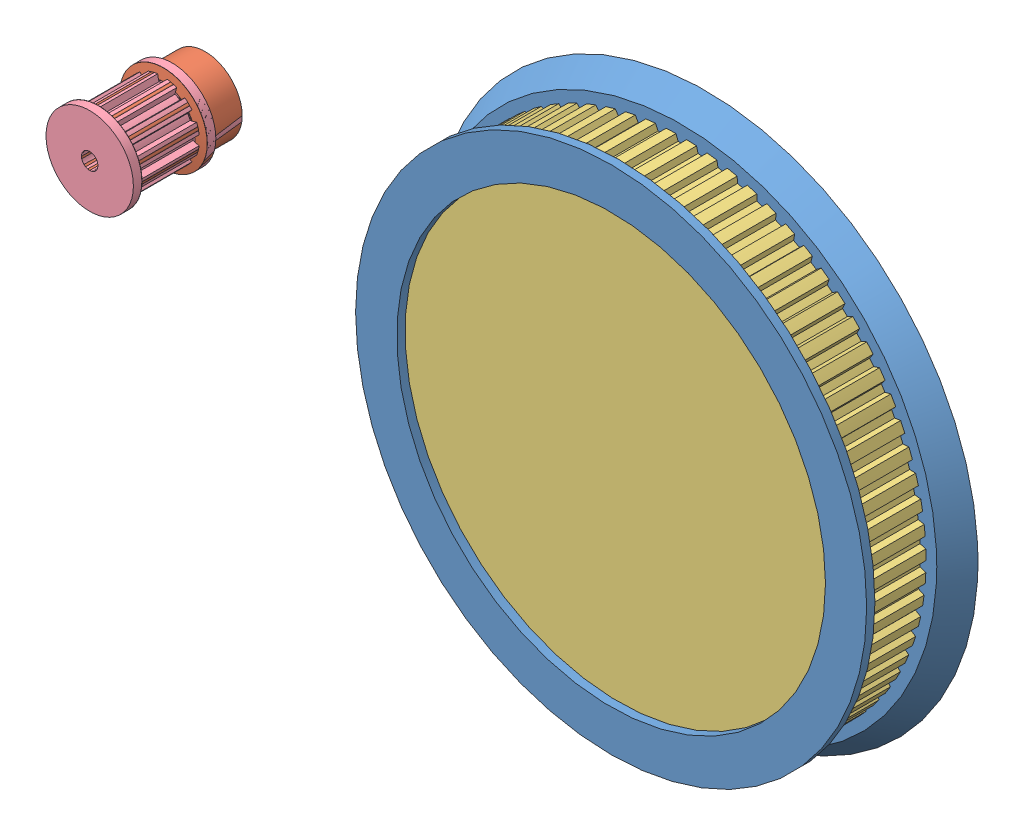
SolidWorks assembly Riemen, configuration Standard. Lengths in mm.
Overall size (115.5 80 14).
4 component instances, 4 part files, 13 mates.
Components (placement in the parent):
- Rad-Hinten-Zahnkranz-Riemen-1: Rad-Hinten-Zahnkranz-Riemen [Standard] at (0 0 -3.75) size (66 66 11.5)
- Zahnriemenrad T2.5 B6 bis Z20-1: Zahnriemenrad T2.5 B6 bis Z20 [Z12] at (-63 0 -3.75) x (1 0 0) z (0 0 -1) size (10.6 10.6 14)
- Zahnriemenrad T2.5 B6 Z75 old-1: Zahnriemenrad T2.5 B6 Z75 old [Standard] at (0 0 -3.75) x (0.999832 -0.018325 0) z (0 0 1) size (59.39 59.4 7.5)
- Mädler 16051200 Zahnriemenrad T2.5 B6 Z12-1: Mädler 16051200 Zahnriemenrad T2.5 B6 Z12 [Standard] at (-63 0 1.25) x (0 0 -1) z (1 0 0) size (14 10.6 10.6)
Mates (geometry in assembly coordinates):
- Deckungsgleich1: coincident anti-aligned: plane of Rad-Hinten-Zahnkranz-Riemen-1 through (0 0 0) normal (0 0 -1); plane of assembly through (0 0 0) normal (0 0 1)
- Deckungsgleich2: coincident anti-aligned: plane of Zahnriemenrad T2.5 B6 bis Z20-1 through (-63 0 0) normal (0 0 -1); plane of assembly through (0 0 0) normal (0 0 1)
- Deckungsgleich3: coincident aligned: plane of Rad-Hinten-Zahnkranz-Riemen-1 through (0 0 -3.75) normal (0 1 0); plane of assembly through (0 0 0) normal (0 1 0)
- Deckungsgleich4: coincident anti-aligned: plane of Zahnriemenrad T2.5 B6 bis Z20-1 through (-63 0 -3.75) normal (0 -1 0); plane of assembly through (0 0 0) normal (0 1 0)
- Deckungsgleich5: coincident aligned: plane of Rad-Hinten-Zahnkranz-Riemen-1 through (0 0 -3.75) normal (1 0 0); plane of assembly through (0 0 0) normal (1 0 0)
- Abstand1: distance = 63 mm aligned: plane of Zahnriemenrad T2.5 B6 bis Z20-1; plane of assembly through (0 0 0) normal (1 0 0)
- Deckungsgleich6: coincident aligned: plane of Zahnriemenrad T2.5 B6 Z75 old-1 through (0 0 0) normal (0 0 1); plane of assembly through (0 0 0) normal (0 0 1)
- Winkel2: planar angle = 0.018326 rad aligned: plane of Zahnriemenrad T2.5 B6 Z75 old-1; plane of assembly through (0 0 0) normal (1 0 0)
- Deckungsgleich9: coincident: line of Zahnriemenrad T2.5 B6 Z75 old-1 through (0 0 0.375) axis (0 0 -1); plane of assembly
- Deckungsgleich10: coincident anti-aligned: plane of Mädler 16051200 Zahnriemenrad T2.5 B6 Z12-1 through (-59.3152 2.3643 0) normal (0 0 -1); plane of assembly through (0 0 0) normal (0 0 1)
- Konzentrisch1: concentric anti-aligned: cylinder of Zahnriemenrad T2.5 B6 bis Z20-1 through (-63 0 -12.75) axis (0 0 1) radius 4.5; cylinder of Mädler 16051200 Zahnriemenrad T2.5 B6 Z12-1 through (-63 0 6.1997) axis (0 0 -1) radius 1
- Deckungsgleich11: coincident: line of Zahnriemenrad T2.5 B6 Z75 old-1 through (0 0 0.375) axis (0 0 -1); plane of assembly
- Deckungsgleich12: coincident aligned: plane of Mädler 16051200 Zahnriemenrad T2.5 B6 Z12-1; plane of assembly through (0 0 0) normal (0 1 0)
